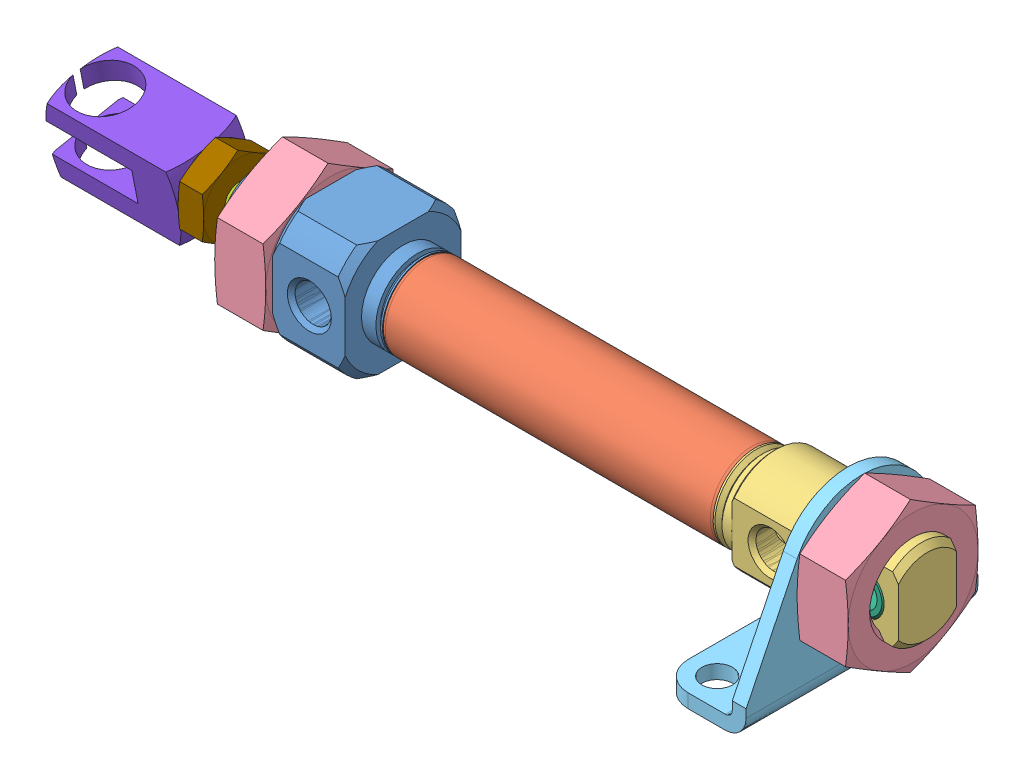
SolidWorks assembly HL-0070_7-DXP(R,D-26765)(F,D-26690), configuration Default. Lengths in mm.
Overall size (93.09 19.34 25.4).
12 component instances, 11 part files, 31 mates.
Components (placement in the parent):
- HL-0070_7-DXP(R,D-26765)(F,D-26690)0000_0_dummy-1: HL-0070_7-DXP(R,D-26765)(F,D-26690)0000_0_dummy [Default] at origin
- 007R000-0_rod_guide-1: 007R000-0_rod_guide [Default] at origin size (21.46 12.7 12.7)
- 007R-1_4390-1: 007R-1_4390 [Default] at (17.9959 0 0) size (37.52 9.12 9.12)
- 007P0Y010_rear_head-1: 007P0Y010_rear_head [Default] at (51.0794 0 0) size (22.23 11.13 10.12)
- D-801-1: D-801 [Default] at (66.1492 0 0) x (0 0 -1) z (-1 0 0) size (14.22 16.42 5.59)
- D-26765-1: D-26765 [Default] at (66.1492 -11.1252 -12.7) x (0 0 1) z (-1 0 0) size (25.4 19.05 9.53)
- D-25359-1: D-25359 [Default] at (69.342 0 0) x (1 0 0) z (0 0 -1) size (4.81 4.81 6.35)
- D-801-2: D-801 [Default] at (7.9248 0 0) x (0 0 -1) z (1 0 0) size (14.22 16.42 5.59)
- HL-0070_7-DXP0_rod-1: HL-0070_7-DXP0_rod [Default] x (1 0 0) z (0 -0.981278 -0.192598) size (60.73 8.06 8.06)
- D-26690-dummy-1: D-26690-dummy [Default] at (-16.002 0 0) x (1 0 0) z (0 -0.981278 -0.192598)
- D-26646-1: D-26646 [Default] at (-16.002 0 0) x (1 0 0) z (0 0.981278 0.192598) size (15.7 7.87 7.87)
- D-3745-1: D-3745 [Default] at (-4.8768 0 0) x (0 0 1) z (-1 0 0) size (7.8 9 2.79)
Mates (geometry in assembly coordinates):
- Distance2: distance = 0 mm aligned: plane of 007R000-0_rod_guide-1 through (0 0 0) normal (1 0 0); plane of HL-0070_7-DXP(R,D-26765)(F,D-26690)0000_0_dummy-1 through (0 0 0) normal (1 0 0)
- Coincident1: coincident aligned: line of HL-0070_7-DXP(R,D-26765)(F,D-26690)0000_0_dummy-1 through (80.9 0 0) axis (-1 0 0); line of 007R000-0_rod_guide-1 through (80.9 0 0) axis (-1 0 0)
- Angle3: planar angle = 0 rad aligned: plane of 007R000-0_rod_guide-1 through (0 0 0) normal (0 0 -1); plane of HL-0070_7-DXP(R,D-26765)(F,D-26690)0000_0_dummy-1 through (0 0 0) normal (0 0 -1)
- Distance4: distance = 0 mm aligned: plane of 007R-1_4390-1 through (17.9959 0 0) normal (1 0 0); plane of 007R000-0_rod_guide-1 through (17.9959 0 0) normal (1 0 0)
- Coincident2: coincident aligned: line of 007R000-0_rod_guide-1 through (80.9 0 0) axis (-1 0 0); line of 007R-1_4390-1 through (98.8959 0 0) axis (-1 0 0)
- Angle6: planar angle = 0 rad aligned: plane of 007R-1_4390-1 through (17.9959 0 0) normal (0 0 -1); plane of 007R000-0_rod_guide-1 through (0 0 0) normal (0 0 -1)
- Distance6: distance = 0 mm aligned: plane of 007P0Y010_rear_head-1 through (54.5465 0 0) normal (1 0 0); plane of 007R-1_4390-1 through (54.5465 0 0) normal (1 0 0)
- Coincident3: coincident aligned: line of 007R-1_4390-1 through (98.8959 0 0) axis (-1 0 0); line of 007P0Y010_rear_head-1 through (131.9794 0 0) axis (-1 0 0)
- Angle9: planar angle = 0 rad aligned: plane of 007P0Y010_rear_head-1 through (51.0794 0 0) normal (0 0 -1); plane of 007R-1_4390-1 through (17.9959 0 0) normal (0 0 -1)
- Distance7: distance = 1.5189 mm anti-aligned: plane of D-801-1 through (66.1492 0 0) normal (-1 0 0); plane of 007P0Y010_rear_head-1 through (64.6303 0 0) normal (1 0 0)
- Coincident4: coincident anti-aligned: line of 007P0Y010_rear_head-1 through (131.9794 0 0) axis (-1 0 0); line of D-801-1 through (-14.7508 0 0) axis (1 0 0)
- Angle12: planar angle = 0 rad aligned: plane of D-801-1; plane of 007P0Y010_rear_head-1 through (51.0794 0 0) normal (0 0 -1)
- Distance8: distance = 0 mm anti-aligned: plane of D-26765-1 through (64.6303 -11.1252 -12.7) normal (-1 0 0); plane of 007P0Y010_rear_head-1 through (64.6303 0 0) normal (1 0 0)
- Coincident5: coincident anti-aligned: line of 007P0Y010_rear_head-1 through (131.9794 0 0) axis (-1 0 0); line of D-26765-1 through (-14.7508 0 0) axis (1 0 0)
- Angle13: planar angle = 0 rad anti-aligned: plane of D-26765-1 through (66.1492 -11.1252 0) normal (0 0 1); plane of 007P0Y010_rear_head-1 through (51.0794 0 0) normal (0 0 -1)
- Distance9: distance = 0 mm anti-aligned: plane of D-25359-1 through (69.342 0 0) normal (0 0 -1); plane of 007P0Y010_rear_head-1 through (51.0794 0 0) normal (0 0 1)
- Coincident6: coincident anti-aligned: line of 007P0Y010_rear_head-1 through (69.342 0 80.9) axis (0 0 -1); line of D-25359-1 through (69.342 0 -80.9) axis (0 0 1)
- Angle16: planar angle = 0 rad aligned: plane of D-25359-1; plane of 007P0Y010_rear_head-1 through (69.342 0 0) normal (1 0 0)
- Distance11: distance = 0 mm aligned: plane of D-801-2 through (7.9248 0 0) normal (1 0 0); plane of 007R000-0_rod_guide-1 through (7.9248 0 0) normal (1 0 0)
- Coincident7: coincident aligned: line of 007R000-0_rod_guide-1 through (80.9 0 0) axis (-1 0 0); line of D-801-2 through (88.8248 0 0) axis (-1 0 0)
- Angle19: planar angle = 0 rad aligned: plane of D-801-2 through (7.9248 0 0) normal (0 0 -1); plane of 007R000-0_rod_guide-1 through (0 0 0) normal (0 0 -1)
- LimitDistance2: limit distance = 0 mm aligned: plane of HL-0070_7-DXP0_rod-1; plane of 007R000-0_rod_guide-1 through (0 0 0) normal (1 0 0)
- Coincident8: coincident aligned: line of 007R000-0_rod_guide-1 through (80.9 0 0) axis (-1 0 0); line of HL-0070_7-DXP0_rod-1 through (80.9 0 0) axis (-1 0 0)
- Distance13: distance = 0 mm aligned: plane of D-26690-dummy-1; plane of HL-0070_7-DXP0_rod-1
- Coincident9: coincident aligned: line of HL-0070_7-DXP0_rod-1 through (80.9 0 0) axis (-1 0 0); line of D-26690-dummy-1 through (64.898 0 0) axis (-1 0 0)
- Angle22: planar angle = 0 rad aligned: plane of D-26690-dummy-1; plane of HL-0070_7-DXP0_rod-1
- Distance14: distance = 0 mm anti-aligned: plane of D-26646-1 through (-16.002 0 0) normal (0 0.981278 0.192598); plane of D-26690-dummy-1 through (-16.002 0 0) normal (0 -0.981278 -0.192598)
- Coincident10: coincident anti-aligned: line of D-26690-dummy-1 through (-16.002 -79.3854 -15.5812) axis (0 0.981278 0.192598); line of D-26646-1 through (-16.002 79.3854 15.5812) axis (0 -0.981278 -0.192598)
- Angle25: planar angle = 0 rad aligned: plane of D-26646-1; plane of D-26690-dummy-1
- Coincident17: coincident anti-aligned: plane of D-26646-1; plane of D-3745-1 through (-4.8768 0 0) normal (-1 0 0)
- Coincident18: coincident anti-aligned: line of D-26646-1 through (64.898 0 0) axis (-1 0 0); line of D-3745-1 through (-85.7768 0 0) axis (1 0 0)
